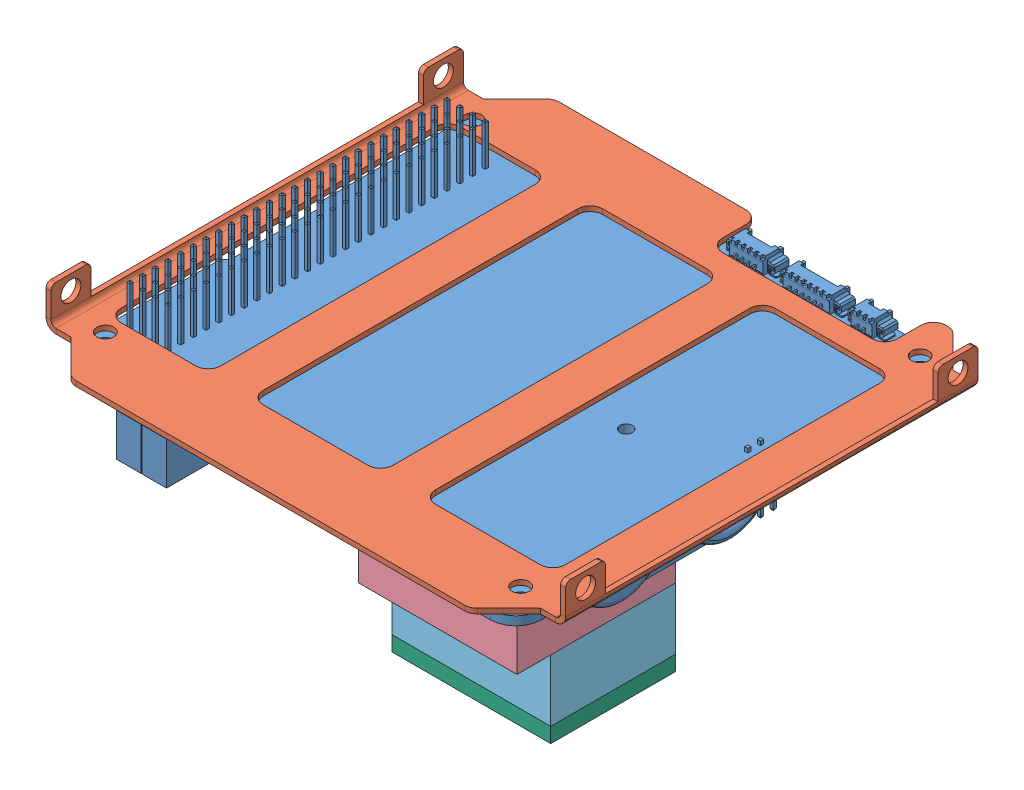
SolidWorks assembly Spirit2U - Battery Shelf, configuration Default. Lengths in mm.
Overall size (104.07 62 96.74).
6 component instances, 6 part files, 16 mates.
Components (placement in the parent):
- Battery-1: Battery [Default] at (93.2994 -3.7424 -1.7701) x (-1 0 0) z (0 -1 0) size (92.92 89.28 30.75)
- Spirit2U Battery Shelf-1: Spirit2U Battery Shelf [Default] at origin size (104.07 8 96.74)
- Spirit2U Battery Thermal Paste-1: Spirit2U Battery Thermal Paste [Default] at (67.0314 -22.2424 -41.6481) x (0 0 -1) z (-1 0 0) size (31.75 3 28.67)
- Upper PCM Heat Sink-1: Upper PCM Heat Sink [Default] at (52.6974 -31.6799 -41.6481) x (1 0 0) z (0 -1 0) size (31.75 31.75 15.88)
- OBC Thermal Strap-1: OBC Thermal Strap [Default] at (52.6974 -39.6174 -45.0231) x (1 0 0) z (0 -1 0) size (31.75 25 12.38)
- OBC Thermal Paste-1: OBC Thermal Paste [Default] at (52.6974 -55 -45.0231) x (1 0 0) z (0 0 1) size (31.75 3 25)
Mates (geometry in assembly coordinates):
- Distance5: distance = 1 mm: plane of Battery-1 through (92.3094 -2 -1.8051) normal (0 1 0); plane of Spirit2U Battery Shelf-1 through (0 -1 0) normal (0 -1 0)
- Distance6: distance = 4.5 mm: plane of Battery-1 through (4.5 -2 -4.2657) normal (-1 0 0); plane of Spirit2U Battery Shelf-1 through (0 0 0) normal (-1 0 0)
- Distance8: distance = 3.7 mm: plane of Battery-1 through (18.7035 -2 -85.9711) normal (0 0 -1); point of Spirit2U Battery Shelf-1
- Coincident1: coordinate: point of Spirit2U Battery Shelf-1; point of assembly
- Concentric161: concentric: cylinder of Battery-1 through (84.8194 -12.7424 -52.5481) axis (-1 0 0) radius 9; cylinder of Spirit2U Battery Thermal Paste-1 through (38.3634 -12.7424 -52.5481) axis (1 0 0) radius 9
- Concentric162: concentric: cylinder of Battery-1 through (20.6694 -12.7424 -30.7481) axis (1 0 0) radius 9; cylinder of Spirit2U Battery Thermal Paste-1 through (38.3634 -12.7424 -30.7481) axis (1 0 0) radius 9
- Coincident311: coincident: plane of Battery-1 through (38.3634 -18.8502 -41.6481) normal (1 0 0); plane of Spirit2U Battery Thermal Paste-1 through (38.3634 -12.7424 -52.5481) normal (-1 0 0)
- Coincident313: coincident: plane of Spirit2U Battery Thermal Paste-1 through (38.3634 -23.7424 -25.7731) normal (0 -1 0); plane of Upper PCM Heat Sink-1 through (52.6974 -23.7424 -41.6481) normal (0 1 0)
- Width1: width: plane of Spirit2U Battery Thermal Paste-1 through (38.3634 -20.7424 -57.5231) normal (0 0 -1); plane of Spirit2U Battery Thermal Paste-1 through (38.3634 -20.7424 -25.7731) normal (0 0 1); plane of Upper PCM Heat Sink-1 through (36.8224 -39.6174 -25.7731) normal (0 0 1); plane of Upper PCM Heat Sink-1 through (36.8224 -39.6174 -57.5231) normal (0 0 -1)
- Width2: width: plane of Spirit2U Battery Thermal Paste-1 through (67.0314 -12.7424 -52.5481) normal (1 0 0); plane of Spirit2U Battery Thermal Paste-1 through (38.3634 -12.7424 -52.5481) normal (-1 0 0); plane of Upper PCM Heat Sink-1 through (36.8224 -39.6174 -57.5231) normal (-1 0 0); plane of Upper PCM Heat Sink-1 through (68.5724 -39.6174 -57.5231) normal (1 0 0)
- Coincident314: coincident: plane of Upper PCM Heat Sink-1 through (52.6974 -39.6174 -41.6481) normal (0 -1 0); plane of OBC Thermal Strap-1 through (52.6974 -39.6174 -45.0231) normal (0 1 0)
- Coincident315: coincident: plane of Upper PCM Heat Sink-1 through (68.5724 -39.6174 -57.5231) normal (1 0 0); plane of OBC Thermal Strap-1 through (68.5724 -52 -57.5231) normal (1 0 0)
- Coincident316: coincident: plane of Upper PCM Heat Sink-1 through (36.8224 -39.6174 -57.5231) normal (0 0 -1); plane of OBC Thermal Strap-1 through (36.8224 -52 -57.5231) normal (0 0 -1)
- Coincident317: coincident: plane of OBC Thermal Strap-1 through (36.8224 -52 -57.5231) normal (0 0 -1); plane of OBC Thermal Paste-1 through (36.8224 -52 -57.5231) normal (0 0 -1)
- Coincident318: coincident: plane of OBC Thermal Strap-1 through (52.6974 -52 -45.0231) normal (0 -1 0); plane of OBC Thermal Paste-1 through (52.6974 -52 -45.0231) normal (0 1 0)
- Coincident319: coincident: plane of OBC Thermal Strap-1 through (68.5724 -52 -57.5231) normal (1 0 0); plane of OBC Thermal Paste-1 through (68.5724 -52 -32.5231) normal (1 0 0)
